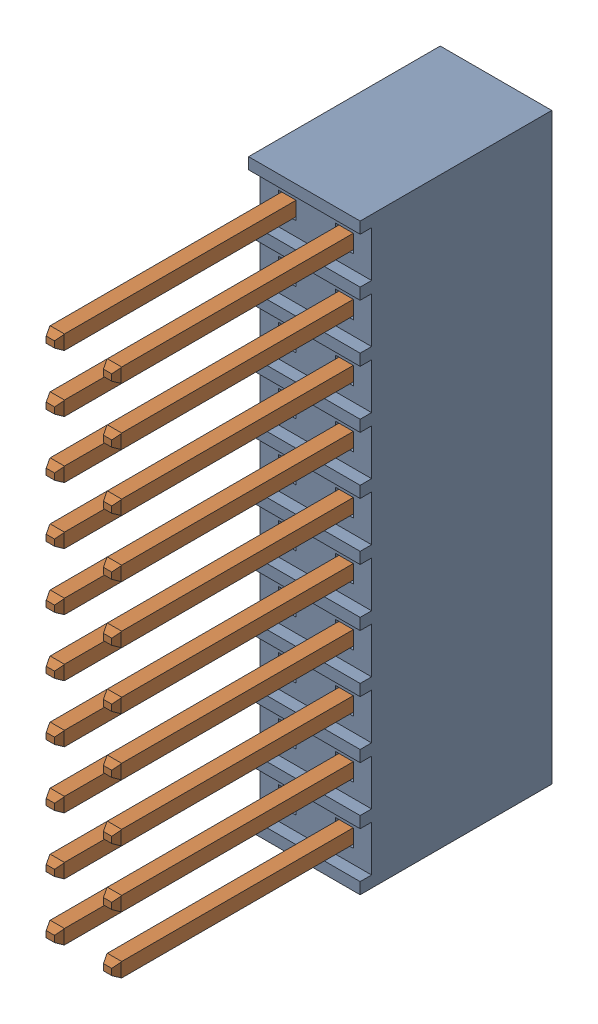
SolidWorks assembly J3, configuration Default. Lengths in mm.
Overall size (4.95 25.91 18.52).
3 component instances, 2 part files, 0 mates.
Components (placement in the parent):
- SSQ-110-03-T-D-1: SSQ-110-03-T-D [Default] at (6.3499 19.0499 -1.6154) x (0 -1 0) z (1 0 0) size (25.91 18.52 4.95)
  - SSQ-110-03-T-D_2-1: SSQ-110-03-T-D_2 [Default] at origin size (25.91 8.51 4.95)
  - SSQ-110-03-T-D_1-1: SSQ-110-03-T-D_1 [Default] at (0 -10.0076 0) size (23.9 11.02 3.76)
